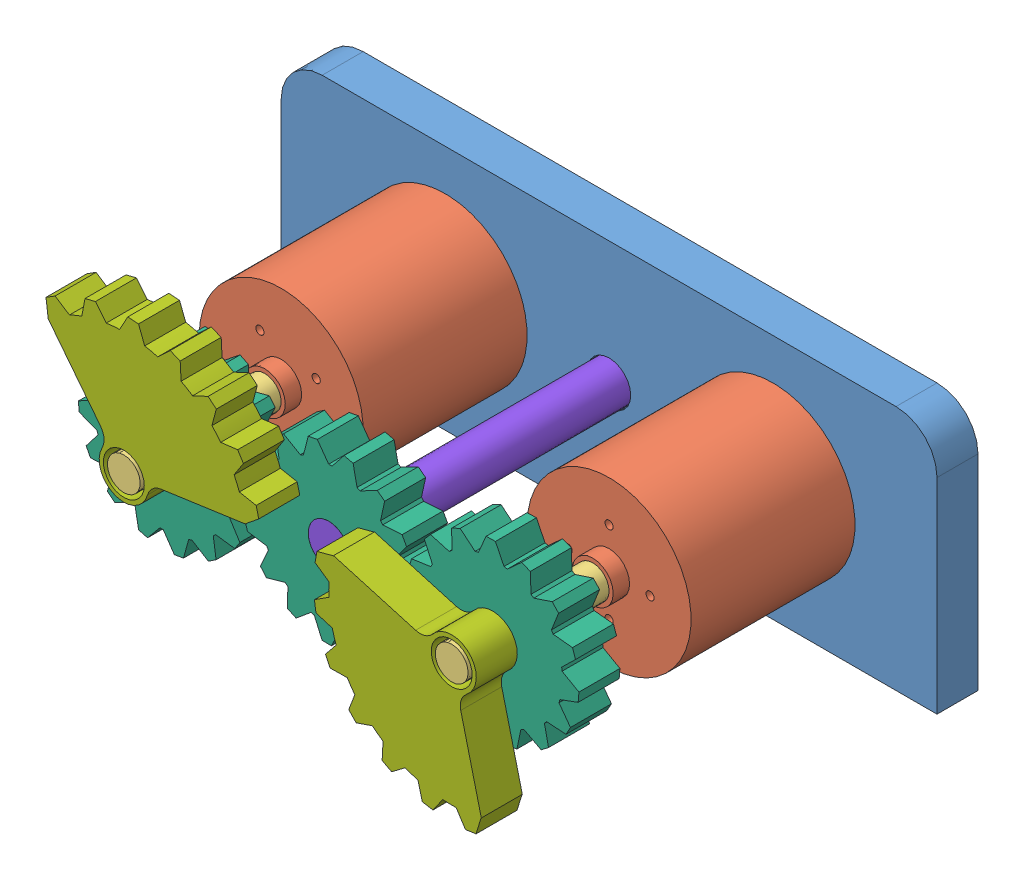
SolidWorks assembly Main assembly, configuration Default. Lengths in mm.
Overall size (80 37.19 50).
19 component instances, 8 part files, 19 mates.
Components (placement in the parent):
- motor holder-1: motor holder [Default] at (33.3269 70.8172 72.9987) size (80 30 5)
- Motor-1: Motor [Default] at (25.9091 64.8426 109.725) x (0.51883 -0.854877 0) z (0 0 -1) size (20 20 50)
  - motorcover-1: motorcover [Default] at (7.4227 18.4991 11.7262) size (20 20 32)
  - dynamo-1: dynamo [Default] at (7.4227 18.4991 32.5262) x (0.962292 0.27202 0) z (0 0 -1) size (15 15 50)
  - Backcover-1: Backcover [Default] at (7.4227 18.4991 40.9262) size (19.2 19.2 0.8)
  - pin-1: pin [Default] at (28.5286 14.4912 41.7262) x (1 0 0) z (0 0 -1) size (1.25 1 1.6)
  - pin-2: pin [Default] at (37.5286 14.4917 41.7262) x (1 0 0) z (0 0 -1) size (1.25 1 1.6)
- Motor-2: Motor [Default] at (46.523 67.3984 109.725) x (1 0 0) z (0 0 -1) size (20 20 50)
  - motorcover-1: motorcover [Default] at (7.4227 18.4991 11.7262) size (20 20 32)
  - dynamo-1: dynamo [Default] at (7.4227 18.4991 32.5262) x (0.962292 0.27202 0) z (0 0 -1) size (15 15 50)
  - Backcover-1: Backcover [Default] at (7.4227 18.4991 40.9262) size (19.2 19.2 0.8)
  - pin-1: pin [Default] at (28.5286 14.4912 41.7262) x (1 0 0) z (0 0 -1) size (1.25 1 1.6)
  - pin-2: pin [Default] at (37.5286 14.4917 41.7262) x (1 0 0) z (0 0 -1) size (1.25 1 1.6)
- Spur gear-1: Spur gear [Default] at (13.9457 48.8992 107.1987) x (-0.96785 0.251527 0) z (0 0 1) size (21.02 20.91 5)
- Spur gear-2: Spur gear [Default] at (53.9457 48.8992 107.1987) x (-0.973351 -0.229319 0) z (0 0 1) size (21.02 20.91 5)
- Rack gear-1: Rack gear [Default] at (13.9457 48.8992 112.1987) x (0.990037 0.14081 0) z (0 0 1) size (24.29 19.79 5)
- Rack gear-2: Rack gear [Default] at (53.9457 48.8992 112.1987) x (-0.960989 0.276587 0) z (0 0 1) size (24.29 19.79 5)
- Spur gear-3: Spur gear [Default] at (33.9457 48.8992 107.1987) x (-0.999731 0.023183 0) z (0 0 1) size (21.02 20.91 5)
- Rod1-2: Rod1 [Default] at (33.9457 48.8992 72.1987) size (5 5 40)
Mates (geometry in assembly coordinates):
- Concentric2: concentric anti-aligned: cylinder of motor holder-1 through (13.9457 48.8992 77.9987) axis (0 0 -1) radius 10; cylinder of Motor-1/motorcover-1 through (13.9457 48.8992 67.9987) axis (0 0 1) radius 10
- Distance2: distance = 20 mm aligned: plane of Motor-1/motorcover-1 through (13.9457 48.8992 97.9987) normal (0 0 1); plane of motor holder-1 through (33.3269 70.8172 77.9987) normal (0 0 1)
- Concentric3: concentric anti-aligned: cylinder of motor holder-1 through (53.9457 48.8992 77.9987) axis (0 0 -1) radius 10; cylinder of Motor-2/motorcover-1 through (53.9457 48.8992 67.9987) axis (0 0 1) radius 10
- Distance3: distance = 20 mm aligned: plane of motor holder-1 through (33.3269 70.8172 77.9987) normal (0 0 1); plane of Motor-2/motorcover-1 through (53.9457 48.8992 97.9987) normal (0 0 1)
- Concentric4: concentric aligned: cylinder of Motor-1/dynamo-1 through (13.9457 48.8992 117.1987) axis (0 0 -1) radius 2; cylinder of Spur gear-1 through (13.9457 48.8992 112.1987) axis (0 0 -1) radius 2.5
- Distance4: distance = 5 mm aligned: plane of Motor-1/dynamo-1 through (13.9457 48.8992 117.1987) normal (0 0 1); plane of Spur gear-1 through (13.9457 48.8992 112.1987) normal (0 0 1)
- Concentric5: concentric aligned: cylinder of Motor-2/dynamo-1 through (53.9457 48.8992 117.1987) axis (0 0 -1) radius 2; cylinder of Spur gear-2 through (53.9457 48.8992 112.1987) axis (0 0 -1) radius 2.5
- Distance5: distance = 5 mm aligned: plane of Spur gear-2 through (53.9457 48.8992 112.1987) normal (0 0 1); plane of Motor-2/dynamo-1 through (53.9457 48.8992 117.1987) normal (0 0 1)
- Concentric6: concentric aligned: cylinder of Motor-1/dynamo-1 through (13.9457 48.8992 117.1987) axis (0 0 -1) radius 2; cylinder of Rack gear-1 through (13.9457 48.8992 117.1987) axis (0 0 -1) radius 2.5
- Coincident7: coincident aligned: plane of Motor-1/dynamo-1 through (13.9457 48.8992 117.1987) normal (0 0 1); plane of Rack gear-1 through (13.9457 48.8992 117.1987) normal (0 0 1)
- Concentric7: concentric aligned: cylinder of Motor-2/dynamo-1 through (53.9457 48.8992 117.1987) axis (0 0 -1) radius 2; cylinder of Rack gear-2 through (53.9457 48.8992 117.1987) axis (0 0 -1) radius 2.5
- Coincident8: coincident aligned: plane of Motor-2/dynamo-1 through (53.9457 48.8992 117.1987) normal (0 0 1); plane of Rack gear-2 through (53.9457 48.8992 117.1987) normal (0 0 1)
- GearMate1: gear = 5 : 5 mm: cylinder of Spur gear-2 through (53.9457 48.8992 112.1987) axis (0 0 -1) radius 2.5; cylinder of Spur gear-1 through (13.9457 48.8992 112.1987) axis (0 0 -1) radius 2.5
- GearMate2: gear = 5 : 5 mm: circle of Spur gear-3; circle of Spur gear-2
- GearMate3: gear = 5 : 5 mm: cylinder of Rack gear-1 through (13.9457 48.8992 117.1987) axis (0 0 -1) radius 2.5; cylinder of Rack gear-2 through (53.9457 48.8992 117.1987) axis (0 0 -1) radius 2.5
- GearMate4: gear = 5 : 5 mm: cylinder of Rack gear-1 through (13.9457 48.8992 117.1987) axis (0 0 -1) radius 2.5; cylinder of Spur gear-1 through (13.9457 48.8992 112.1987) axis (0 0 -1) radius 2.5
- Concentric12: concentric aligned: cylinder of motor holder-1 through (33.9457 48.8992 77.9987) axis (0 0 -1) radius 2.641; cylinder of Rod1-2 through (33.9457 48.8992 112.1987) axis (0 0 -1) radius 2.5
- Coincident23: coincident aligned: plane of Spur gear-3 through (33.9457 48.8992 112.1987) normal (0 0 1); plane of Rod1-2 through (33.9457 48.8992 112.1987) normal (0 0 1)
- GearMate5: gear = 5 : 5 mm: circle of Rack gear-1; circle of Rack gear-2
